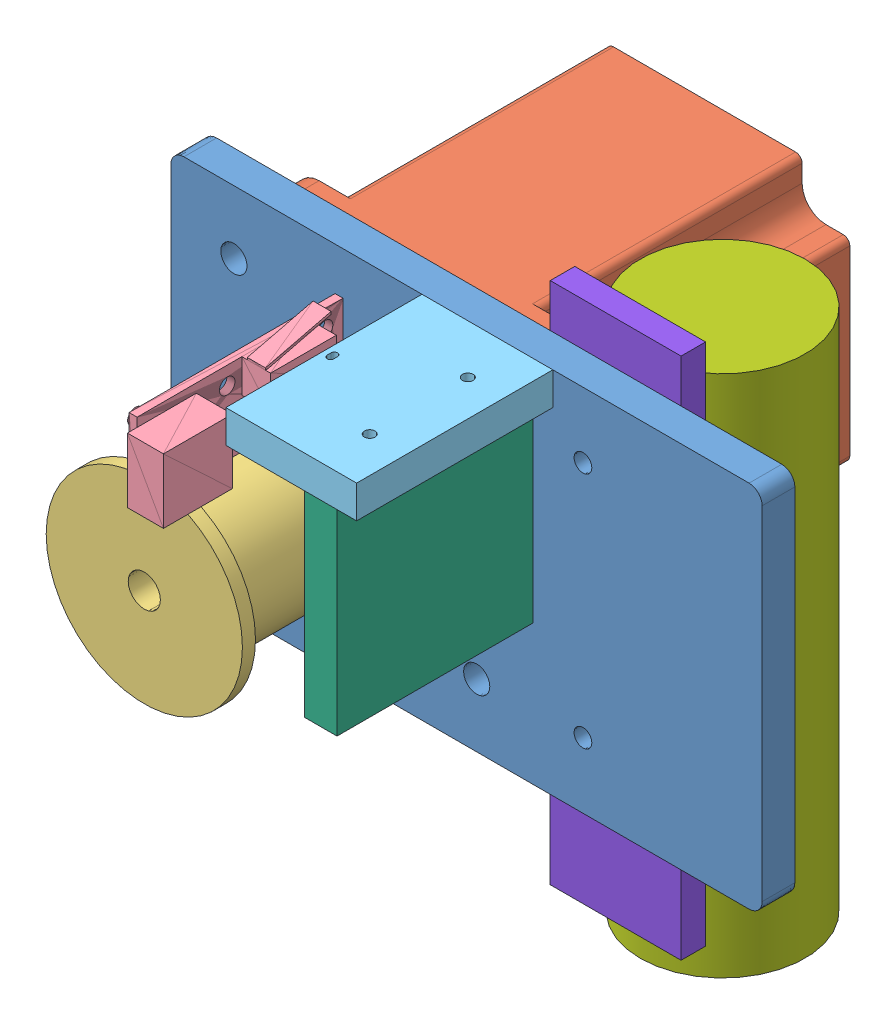
SolidWorks assembly pulley_unit, configuration Default. Lengths in mm.
Overall size (114.82 110.01 118.02).
8 component instances, 8 part files, 22 mates.
Components (placement in the parent):
- motor_plate-1: motor_plate [Default] at (-27.3393 0.6329 -0.9306) size (114.82 71.64 6.35)
- anaheim_stepper_nema23-1: anaheim_stepper_nema23 [Default] at (-27.3393 0.6329 -11.3186) size (56.4 56.4 76.88)
- spindle1-1: spindle1 [Default] at (-27.3393 0.6329 20.9894) x (0 0 1) z (-1 0 0) size (50.8 38.1 38.1)
- mechanical_endstop-1: mechanical_endstop [Default] at (-22.9453 36.4529 13.7444) x (0 0 1) z (1 0 0) size (41.88 19.5 9.76)
- string_plate-1: string_plate [Default] at (-1.6853 30.1029 24.4694) x (1 0 0) z (0 1 0) size (25.4 38.1 6.35)
- support_plate-1: support_plate [Default] at (0.8607 11.0529 24.4694) x (0 1 0) z (1 0 0) size (38.1 38.1 6.35)
- cstand_pipe-1: cstand_pipe [Default] at (16.8627 -65.1471 -21.6951) x (0 0 1) z (0 1 0) size (32 32 101.6)
- mount_bar-1: mount_bar [Default] at (16.8627 -5.9409 -5.6931) size (25.4 101.6 4.76)
Mates (geometry in assembly coordinates):
- Concentric1: concentric aligned: cylinder of motor_plate-1 through (-50.9093 -22.9371 5.4194) axis (0 0 -1) radius 2.55; cylinder of anaheim_stepper_nema23-1 through (-50.9093 -22.9371 -6.5186) axis (0 0 -1) radius 2.55
- Concentric2: concentric aligned: cylinder of motor_plate-1 through (-3.7693 24.2029 5.4194) axis (0 0 -1) radius 2.55; cylinder of anaheim_stepper_nema23-1 through (-3.7693 24.2029 -6.5186) axis (0 0 -1) radius 2.55
- Distance3: distance = 5.588 mm anti-aligned: plane of motor_plate-1 through (49.1207 33.9129 -0.9306) normal (0 0 -1); plane of anaheim_stepper_nema23-1 through (-51.0943 24.3879 -6.5186) normal (0 0 1)
- Concentric3: concentric aligned: cylinder of anaheim_stepper_nema23-1 through (-27.3393 0.6329 14.4814) axis (0 0 -1) radius 3.175; cylinder of spindle1-1 through (-27.3393 0.6329 46.3894) axis (0 0 -1) radius 3.1242
- Distance1: distance = 0.508 mm anti-aligned: plane of spindle1-1 through (-27.3393 6.9829 -4.4106) normal (0 0 -1); plane of anaheim_stepper_nema23-1 through (-27.3393 0.6329 -4.9186) normal (0 0 1)
- Coincident2: coincident aligned: plane of anaheim_stepper_nema23-1 through (-27.3393 0.6329 -11.3186) normal (0 1 0); plane of spindle1-1
- Distance4: distance = 2.54 mm aligned: plane of string_plate-1 through (-1.6853 30.1029 24.4694) normal (0 0 -1); plane of mechanical_endstop-1
- Coincident9: coincident anti-aligned: plane of motor_plate-1 through (49.1207 33.9129 5.4194) normal (0 0 1); plane of string_plate-1 through (-14.3853 36.4529 5.4194) normal (0 0 -1)
- Coincident11: coincident anti-aligned: plane of mechanical_endstop-1 through (-14.3853 36.4529 13.7444) normal (1 0 0); plane of string_plate-1 through (-14.3853 36.4529 43.5194) normal (-1 0 0)
- Coincident12: coincident aligned: plane of mechanical_endstop-1 through (-22.9453 36.4529 13.7444) normal (0 1 0); plane of string_plate-1 through (-1.6853 36.4529 24.4694) normal (0 1 0)
- Tangent1: tangent aligned: cylinder of spindle1-1 through (-27.3393 0.6329 -4.4106) axis (0 0 -1) radius 13.97; plane of string_plate-1 through (-13.3693 30.1029 24.8504) normal (1 0 0)
- Coincident14: coincident anti-aligned: plane of motor_plate-1 through (49.1207 33.9129 5.4194) normal (0 0 1); plane of support_plate-1 through (7.2107 -7.9971 5.4194) normal (0 0 -1)
- Coincident15: coincident anti-aligned: plane of string_plate-1 through (-1.6853 30.1029 24.4694) normal (0 -1 0); plane of support_plate-1 through (7.2107 30.1029 5.4194) normal (0 1 0)
- Parallel1: parallel aligned: plane of motor_plate-1 through (-60.6193 36.4529 5.4194) normal (0 1 0); plane of string_plate-1 through (-1.6853 36.4529 24.4694) normal (0 1 0)
- Distance6: distance = 0.508 mm anti-aligned: cylinder of spindle1-1 through (-27.3393 0.6329 -4.4106) axis (0 0 -1) radius 19.05; plane of mechanical_endstop-1 through (-22.9453 20.1909 13.7444) normal (0 -1 0)
- Tangent3: tangent anti-aligned: plane of anaheim_stepper_nema23-1 through (0.8607 -23.1221 -6.5186) normal (1 0 0); cylinder of cstand_pipe-1 through (16.8627 36.4529 -21.6951) axis (0 -1 0) radius 16.002
- Coincident16: coincident aligned: plane of motor_plate-1 through (-60.6193 36.4529 5.4194) normal (0 1 0); plane of cstand_pipe-1 through (16.8627 36.4529 -21.6951) normal (0 1 0)
- Coincident17: coincident anti-aligned: plane of motor_plate-1 through (49.1207 33.9129 -0.9306) normal (0 0 -1); plane of mount_bar-1 through (16.8627 -5.9409 -0.9306) normal (0 0 1)
- Coincident18: coincident aligned: plane of cstand_pipe-1; plane of mount_bar-1 through (16.8627 -5.9409 -5.6931) normal (1 0 0)
- Tangent4: tangent anti-aligned: cylinder of cstand_pipe-1 through (16.8627 36.4529 -21.6951) axis (0 -1 0) radius 16.002; plane of mount_bar-1 through (16.8627 -5.9409 -5.6931) normal (0 0 -1)
- Coincident20: coincident aligned: plane of motor_plate-1 through (-60.6193 36.4529 5.4194) normal (0 1 0); plane of string_plate-1 through (-1.6853 36.4529 24.4694) normal (0 1 0)
- Coincident22: coincident anti-aligned: plane of anaheim_stepper_nema23-1 through (0.8607 -23.1221 -6.5186) normal (1 0 0); plane of support_plate-1 through (0.8607 11.0529 24.4694) normal (-1 0 0)
